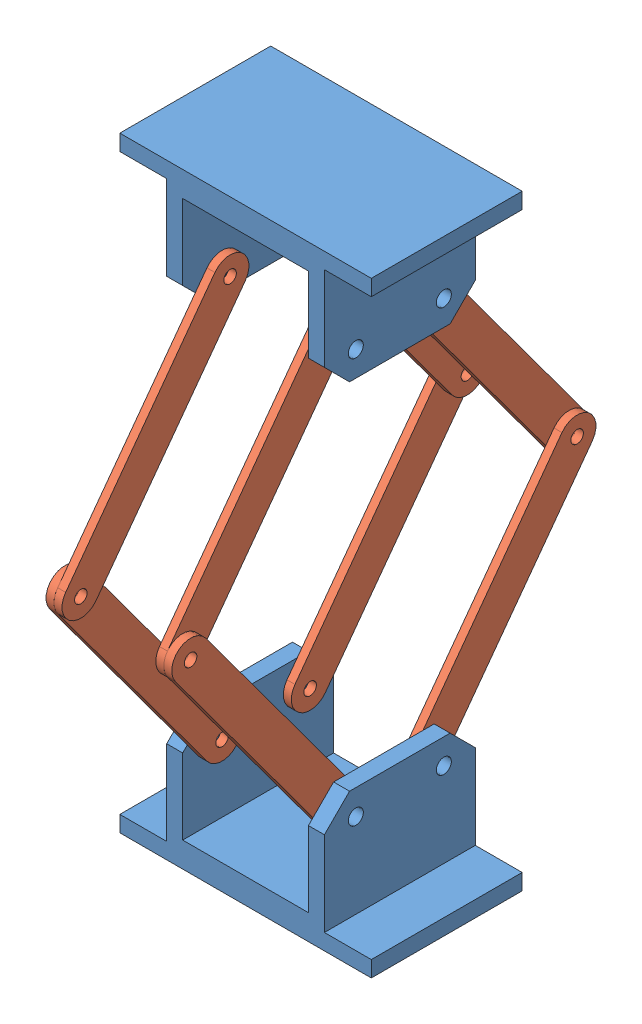
SolidWorks assembly Motagem_Macaco, configuration Valor predeterminado. Lengths in mm.
Overall size (200 481.91 349.38).
10 component instances, 2 part files, 24 mates.
Components (placement in the parent):
- Base_Macaco-1: Base_Macaco [Valor predeterminado] at origin size (200 100 120)
- Haste_Macaco-1: Haste_Macaco [Valor predeterminado] at (43.65 80 35) x (0 0.593574 -0.804779) z (1 0 0) size (30 230 6.35)
- Haste_Macaco-2: Haste_Macaco [Valor predeterminado] at (-43.65 80 35) x (0 -0.593574 0.804779) z (-1 0 0) size (30 230 6.35)
- Haste_Macaco-3: Haste_Macaco [Valor predeterminado] at (43.65 80 -35) x (0 -0.593574 -0.804779) z (1 0 0) size (30 230 6.35)
- Haste_Macaco-4: Haste_Macaco [Valor predeterminado] at (-43.65 80 -35) x (0 0.593574 0.804779) z (-1 0 0) size (30 230 6.35)
- Haste_Macaco-5: Haste_Macaco [Valor predeterminado] at (43.65 240.9559 153.7148) x (0 0.593574 0.804779) z (-1 0 0) size (30 230 6.35)
- Haste_Macaco-6: Haste_Macaco [Valor predeterminado] at (43.65 240.9559 -153.7148) x (0 -0.593574 0.804779) z (-1 0 0) size (30 230 6.35)
- Haste_Macaco-7: Haste_Macaco [Valor predeterminado] at (-43.65 240.9559 -153.7148) x (0 0.593574 -0.804779) z (1 0 0) size (30 230 6.35)
- Haste_Macaco-9: Haste_Macaco [Valor predeterminado] at (-43.65 240.9559 153.7148) x (0 -0.593574 -0.804779) z (1 0 0) size (30 230 6.35)
- Base_Macaco-3: Base_Macaco [Valor predeterminado] at (0 481.9118 0) x (-1 0 0) z (0 0 1) size (200 100 120)
Mates (geometry in assembly coordinates):
- Concêntrico1: concentric anti-aligned: cylinder of Base_Macaco-1 through (-100 80 35) axis (1 0 0) radius 6; cylinder of Haste_Macaco-1 through (50 80 35) axis (-1 0 0) radius 5
- Coincidente1: coincident anti-aligned: plane of Base_Macaco-1 through (50 100 60) normal (-1 0 0); plane of Haste_Macaco-1 through (50 80 35) normal (1 0 0)
- Concêntrico2: concentric aligned: cylinder of Base_Macaco-1 through (-100 80 35) axis (1 0 0) radius 6; cylinder of Haste_Macaco-2 through (-50 80 35) axis (1 0 0) radius 5
- Coincidente2: coincident anti-aligned: plane of Base_Macaco-1 through (-50 100 60) normal (1 0 0); plane of Haste_Macaco-2 through (-50 80 35) normal (-1 0 0)
- Concêntrico3: concentric anti-aligned: cylinder of Base_Macaco-1 through (-100 80 -35) axis (1 0 0) radius 6; cylinder of Haste_Macaco-3 through (50 80 -35) axis (-1 0 0) radius 5
- Coincidente3: coincident anti-aligned: plane of Base_Macaco-1 through (50 100 60) normal (-1 0 0); plane of Haste_Macaco-3 through (50 80 -35) normal (1 0 0)
- Concêntrico4: concentric aligned: cylinder of Base_Macaco-1 through (-100 80 -35) axis (1 0 0) radius 6; cylinder of Haste_Macaco-4 through (-50 80 -35) axis (1 0 0) radius 5
- Coincidente4: coincident anti-aligned: plane of Base_Macaco-1 through (-50 100 60) normal (1 0 0); plane of Haste_Macaco-4 through (-50 80 -35) normal (-1 0 0)
- Concêntrico6: concentric anti-aligned: cylinder of Haste_Macaco-1 through (50 240.9559 153.7148) axis (-1 0 0) radius 5; cylinder of Haste_Macaco-5 through (37.3 240.9559 153.7148) axis (1 0 0) radius 5
- Coincidente5: coincident anti-aligned: plane of Haste_Macaco-1 through (43.65 80 35) normal (-1 0 0); plane of Haste_Macaco-5 through (43.65 240.9559 153.7148) normal (1 0 0)
- Concêntrico7: concentric anti-aligned: cylinder of Haste_Macaco-3 through (50 240.9559 -153.7148) axis (-1 0 0) radius 5; cylinder of Haste_Macaco-6 through (37.3 240.9559 -153.7148) axis (1 0 0) radius 5
- Coincidente6: coincident anti-aligned: plane of Haste_Macaco-3 through (43.65 80 -35) normal (-1 0 0); plane of Haste_Macaco-6 through (43.65 240.9559 -153.7148) normal (1 0 0)
- Concêntrico8: concentric anti-aligned: cylinder of Haste_Macaco-4 through (-50 240.9559 -153.7148) axis (1 0 0) radius 5; cylinder of Haste_Macaco-7 through (-37.3 240.9559 -153.7148) axis (-1 0 0) radius 5
- Coincidente7: coincident anti-aligned: plane of Haste_Macaco-4 through (-43.65 80 -35) normal (1 0 0); plane of Haste_Macaco-7 through (-43.65 240.9559 -153.7148) normal (-1 0 0)
- Concêntrico10: concentric anti-aligned: cylinder of Haste_Macaco-2 through (-50 240.9559 153.7148) axis (1 0 0) radius 5; cylinder of Haste_Macaco-9 through (-37.3 240.9559 153.7148) axis (-1 0 0) radius 5
- Coincidente8: coincident anti-aligned: plane of Haste_Macaco-2 through (-43.65 80 35) normal (1 0 0); plane of Haste_Macaco-9 through (-43.65 240.9559 153.7148) normal (-1 0 0)
- Concêntrico11: concentric anti-aligned: cylinder of Haste_Macaco-5 through (37.3 401.9118 35) axis (1 0 0) radius 5; cylinder of Base_Macaco-3 through (100 401.9118 35) axis (-1 0 0) radius 6
- Concêntrico12: concentric aligned: cylinder of Haste_Macaco-9 through (-37.3 401.9118 35) axis (-1 0 0) radius 5; cylinder of Base_Macaco-3 through (100 401.9118 35) axis (-1 0 0) radius 6
- Concêntrico13: concentric anti-aligned: cylinder of Haste_Macaco-6 through (37.3 401.9118 -35) axis (1 0 0) radius 5; cylinder of Base_Macaco-3 through (100 401.9118 -35) axis (-1 0 0) radius 6
- Concêntrico14: concentric aligned: cylinder of Haste_Macaco-7 through (-37.3 401.9118 -35) axis (-1 0 0) radius 5; cylinder of Base_Macaco-3 through (100 401.9118 -35) axis (-1 0 0) radius 6
- Largura1: width anti-aligned: plane of Base_Macaco-3 through (50 381.9118 60) normal (-1 0 0); plane of Base_Macaco-3 through (-50 381.9118 60) normal (1 0 0); plane of Haste_Macaco-6 through (43.65 240.9559 -153.7148) normal (1 0 0); plane of Haste_Macaco-7 through (-43.65 240.9559 -153.7148) normal (-1 0 0)
- Paralelo1: parallel aligned: plane of Haste_Macaco-2; plane of Haste_Macaco-6
- Paralelo2: parallel anti-aligned: plane of Haste_Macaco-4; plane of Haste_Macaco-9
- Coincidente11: coincident aligned: plane of Base_Macaco-1 through (0 0 0) normal (0 0 1); plane of Base_Macaco-3 through (0 481.9118 0) normal (0 0 1)
